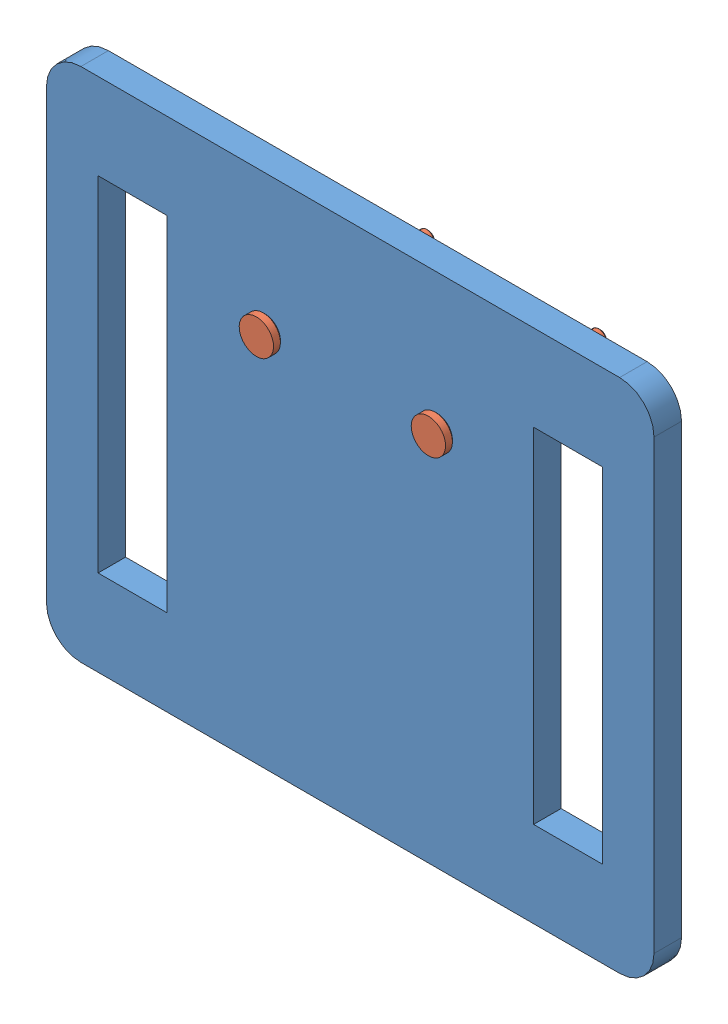
SolidWorks assembly PCB&电流针, configuration 默认. Lengths in mm.
Overall size (35.32 30 10).
3 component instances, 2 part files, 4 mates.
Components (placement in the parent):
- Charging_PCB版型_for_AD21-1: Charging_PCB版型_for_AD21 [默认] at (-152.1489 21.7341 -0.8) size (35.32 30 1.6)
- 电流针_2mm直径10mm长-1: 电流针_2mm直径10mm长 [默认] at (-137.7644 25.2341 1.3) x (0.98041 0.196968 0) z (-0.196968 0.98041 0) size (2 10 2)
- 电流针_2mm直径10mm长-2: 电流针_2mm直径10mm长 [默认] at (-127.7644 25.2341 1.3) x (1 0 0) z (0 1 0) size (2 10 2)
Mates (geometry in assembly coordinates):
- 同心1: concentric anti-aligned: cylinder of Charging_PCB版型_for_AD21-1 through (-137.7644 25.2341 0.8) axis (0 0 -1) radius 0.8; cylinder of 电流针_2mm直径10mm长-1 through (-137.7644 25.2341 -7.7) axis (0 0 1) radius 0.75
- 同心2: concentric anti-aligned: cylinder of Charging_PCB版型_for_AD21-1 through (-127.7644 25.2341 0.8) axis (0 0 -1) radius 0.8; cylinder of 电流针_2mm直径10mm长-2 through (-127.7644 25.2341 -7.7) axis (0 0 1) radius 0.75
- 重合1: coincident anti-aligned: plane of Charging_PCB版型_for_AD21-1 through (-152.1489 21.7341 0.8) normal (0 0 1); plane of 电流针_2mm直径10mm长-1 through (-137.7644 25.2341 0.8) normal (0 0 -1)
- 重合2: coincident anti-aligned: plane of Charging_PCB版型_for_AD21-1 through (-152.1489 21.7341 0.8) normal (0 0 1); circle of 电流针_2mm直径10mm长-2
